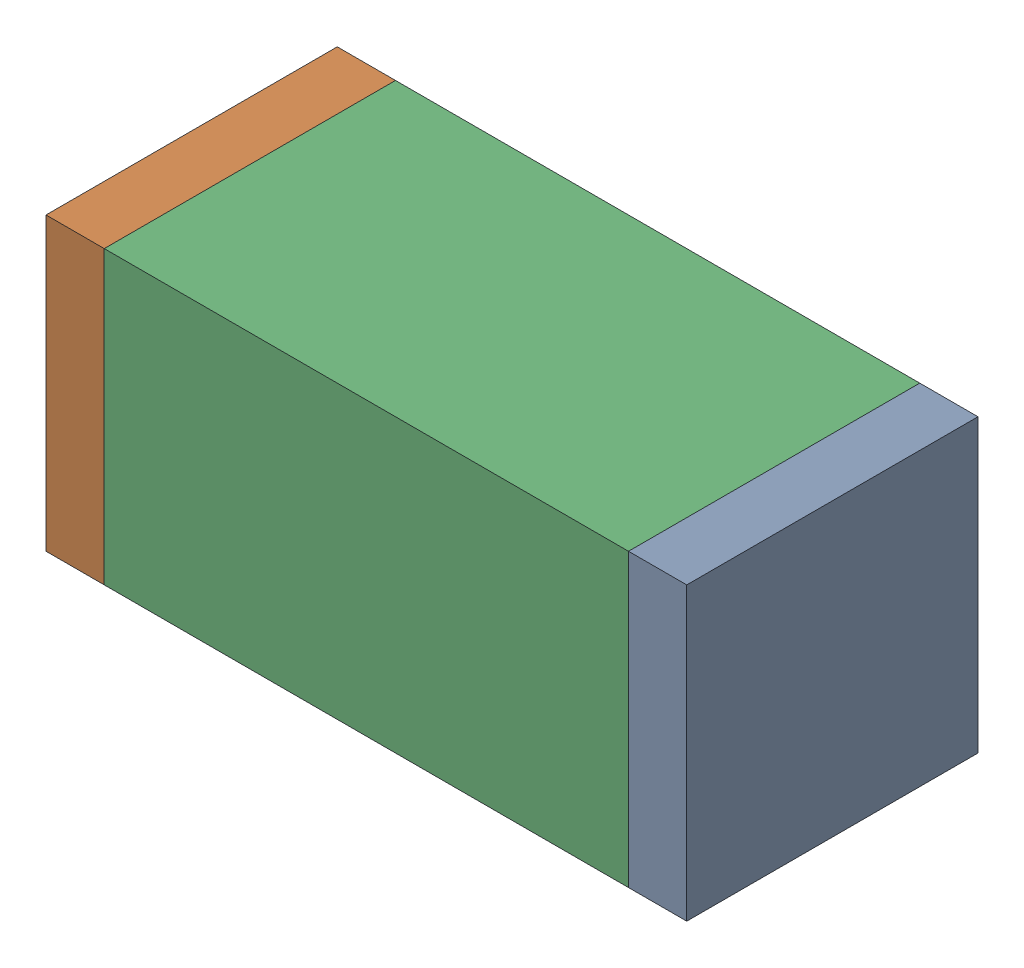
SolidWorks assembly C83, configuration Default. Lengths in mm.
Overall size (1.1 0.5 0.5).
6 component instances, 2 part files, 0 mates.
Components (placement in the parent):
- 810156080-1: 810156080 [Default] at (118.65 61.8 0) size (0.1 0.5 0.5)
  - Extruded_5-1: Extruded_5 [Default] at origin size (0.1 0.5 0.5)
- 810156080-2: 810156080 [Default] at (117.65 61.8 0) size (0.1 0.5 0.5)
  - Extruded_5-1: Extruded_5 [Default] at origin size (0.1 0.5 0.5)
- 836749680-1: 836749680 [Default] at (118.15 61.8 0) size (0.9 0.5 0.5)
  - Extruded_4-1: Extruded_4 [Default] at origin size (0.9 0.5 0.5)
